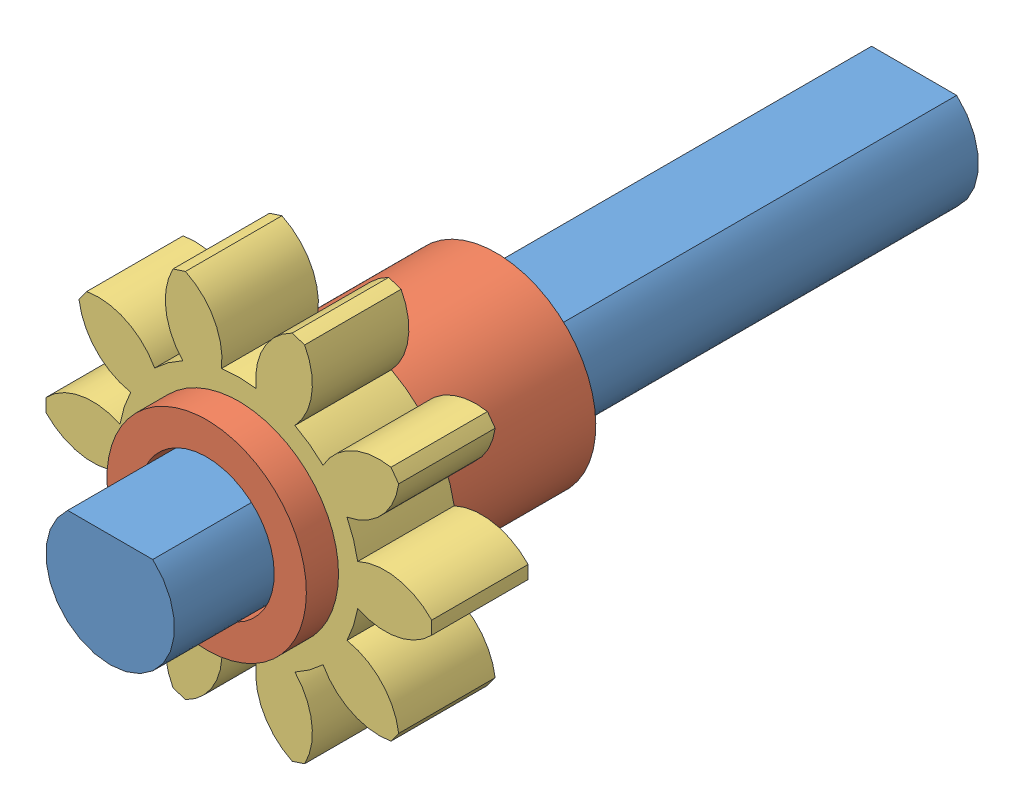
SolidWorks assembly first subassembly, configuration Default. Lengths in mm.
Overall size (12 11.53 25).
4 component instances, 3 part files, 7 mates.
Components (placement in the parent):
- axle-1: axle [25 mm tall] at (8.7951 14.8723 5.9022) size (4 3.5 25)
- spacer-1: spacer [4.2 mm ID] at (8.7951 14.8723 26.9022) x (-0.0222 0.999754 0) z (0 0 1) size (6.2 6.2 1)
- spacer-2: spacer [5mm tall] at (8.7951 14.8723 18.9022) x (-0.292793 -0.956176 0) z (0 0 1) size (6.2 6.2 5)
- root_gear copy-1: root_gear copy [10T 1.0Mod] at (8.7951 14.8723 23.9022) size (12 11.53 3)
Mates (geometry in assembly coordinates):
- Concentric1: concentric anti-aligned: cylinder of axle-1 through (8.7951 14.8723 30.9022) axis (0 0 -1) radius 2; cylinder of root_gear copy-1 through (8.7951 14.8723 16.9022) axis (0 0 1) radius 2
- Concentric3: concentric aligned: cylinder of axle-1 through (8.7951 14.8723 30.9022) axis (0 0 -1) radius 2; cylinder of spacer-1 through (8.7951 14.8723 27.9022) axis (0 0 -1) radius 2.1
- Coincident2: coincident anti-aligned: plane of spacer-1 through (8.7951 14.8723 26.9022) normal (0 0 -1); plane of root_gear copy-1 through (8.7951 14.8723 26.9022) normal (0 0 1)
- Coincident3: coincident anti-aligned: plane of axle-1 through (7.4722 16.3723 30.9022) normal (0 1 0); plane of root_gear copy-1 through (7.4722 16.3723 16.9022) normal (0 -1 0)
- Concentric5: concentric aligned: cylinder of axle-1 through (8.7951 14.8723 30.9022) axis (0 0 -1) radius 2; cylinder of spacer-2 through (8.7951 14.8723 23.9022) axis (0 0 -1) radius 2.1
- Coincident4: coincident anti-aligned: plane of spacer-2 through (8.7951 14.8723 23.9022) normal (0 0 1); plane of root_gear copy-1 through (8.7951 14.8723 23.9022) normal (0 0 -1)
- Distance1: distance = 3 mm aligned: plane of spacer-1 through (8.7951 14.8723 27.9022) normal (0 0 1); plane of axle-1 through (8.7951 14.8723 30.9022) normal (0 0 1)
